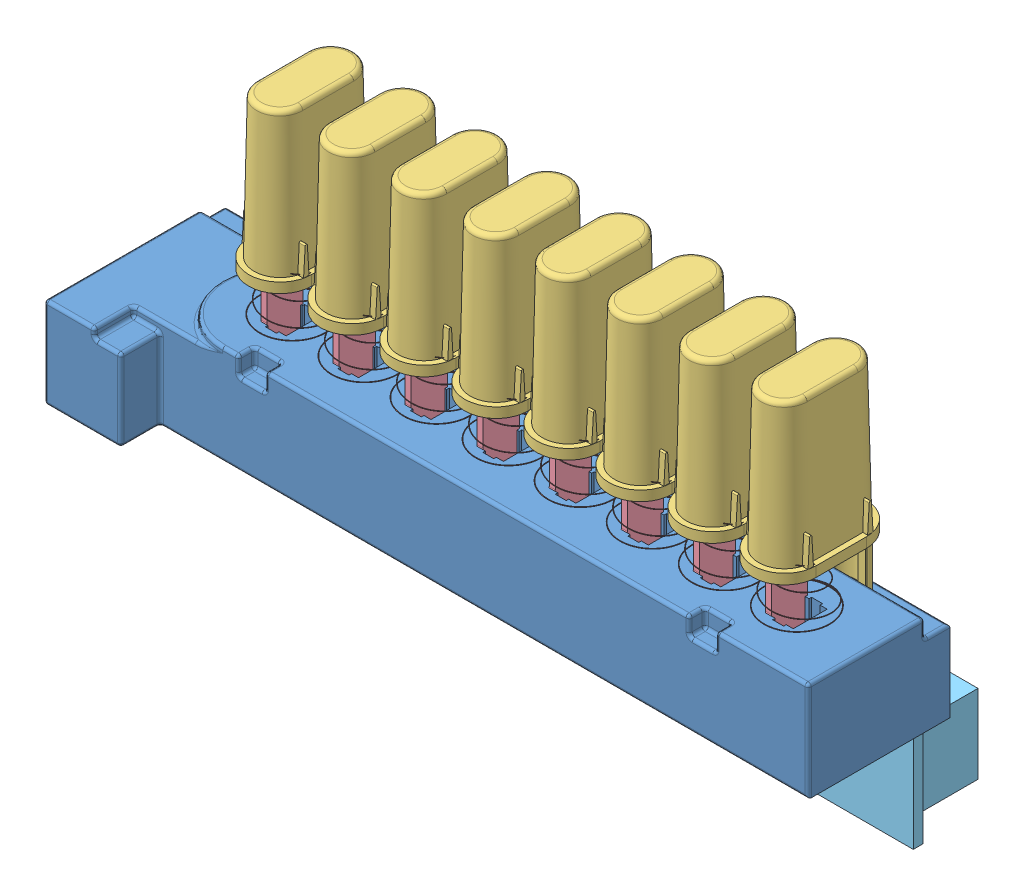
SolidWorks assembly Buttonboxsubassembly, configuration Default. Lengths in mm.
Overall size (116.84 65.25 39.12).
26 component instances, 5 part files, 10 mates.
Components (placement in the parent):
- button box-1: button box [Default] at (46.117 55.4013 86.7134) size (116.84 16 29.21)
- pillaip-spring-1: pillaip-spring [Default] at (11.9321 72.1833 85.5267) size (10.6 9.23 10.6)
- Button-2-1: Button-2 [Default] at (10.105 102.3913 77.544) x (0 0 1) z (1 0 0) size (18.29 33.02 10.16)
- button-key-1: button-key [Default] at (9.6224 72.1653 85.3545) x (0 -1 0) z (0 0 1) size (29.46 0.97 14.24)
- button-key-2: button-key [Default] at (21.2429 72.1653 85.3545) x (0 -1 0) z (0 0 1) size (29.46 0.97 14.24)
- button-key-3: button-key [Default] at (32.8634 72.1653 85.3545) x (0 -1 0) z (0 0 1) size (29.46 0.97 14.24)
- button-key-4: button-key [Default] at (44.4839 72.1653 85.3545) x (0 -1 0) z (0 0 1) size (29.46 0.97 14.24)
- button-key-5: button-key [Default] at (56.1044 72.1653 85.3545) x (0 -1 0) z (0 0 1) size (29.46 0.97 14.24)
- button-key-6: button-key [Default] at (67.7249 72.1653 85.3545) x (0 -1 0) z (0 0 1) size (29.46 0.97 14.24)
- button-key-7: button-key [Default] at (79.3454 72.1653 85.3545) x (0 -1 0) z (0 0 1) size (29.46 0.97 14.24)
- button-key-8: button-key [Default] at (90.9659 72.1653 85.3545) x (0 -1 0) z (0 0 1) size (29.46 0.97 14.24)
- Button-2-2: Button-2 [Default] at (21.7255 102.3913 77.544) x (0 0 1) z (1 0 0) size (18.29 33.02 10.16)
- Button-2-3: Button-2 [Default] at (33.346 102.3913 77.544) x (0 0 1) z (1 0 0) size (18.29 33.02 10.16)
- Button-2-4: Button-2 [Default] at (44.9665 102.3913 77.544) x (0 0 1) z (1 0 0) size (18.29 33.02 10.16)
- Button-2-5: Button-2 [Default] at (56.587 102.3913 77.544) x (0 0 1) z (1 0 0) size (18.29 33.02 10.16)
- Button-2-6: Button-2 [Default] at (68.2075 102.3913 77.544) x (0 0 1) z (1 0 0) size (18.29 33.02 10.16)
- Button-2-7: Button-2 [Default] at (79.828 102.3913 77.544) x (0 0 1) z (1 0 0) size (18.29 33.02 10.16)
- Button-2-8: Button-2 [Default] at (91.4485 102.3913 77.544) x (0 0 1) z (1 0 0) size (18.29 33.02 10.16)
- pillaip-spring-2: pillaip-spring [Default] at (23.5526 72.1833 85.5267) size (10.6 9.23 10.6)
- pillaip-spring-3: pillaip-spring [Default] at (35.1731 72.1833 85.5267) size (10.6 9.23 10.6)
- pillaip-spring-4: pillaip-spring [Default] at (46.7936 72.1833 85.5267) size (10.6 9.23 10.6)
- pillaip-spring-5: pillaip-spring [Default] at (58.4141 72.1833 85.5267) size (10.6 9.23 10.6)
- pillaip-spring-6: pillaip-spring [Default] at (70.0346 72.1833 85.5267) size (10.6 9.23 10.6)
- pillaip-spring-7: pillaip-spring [Default] at (81.6551 72.1833 85.5267) size (10.6 9.23 10.6)
- pillaip-spring-8: pillaip-spring [Default] at (93.2756 72.1833 85.5267) size (10.6 9.23 10.6)
- pillaip-circuitboard-2: pillaip-circuitboard [Default] at (53.1748 50.2958 73.6324) x (-1 0.000001 0) z (0.000001 1 0) size (97.05 12.98 26.31)
Mates (geometry in assembly coordinates):
- Coincident3: coincident anti-aligned: plane of button box-1 through (46.117 57.4333 82.4335) normal (0 0 1); plane of button-key-1 through (140.599 72.1653 82.4335) normal (0 0 -1)
- Coincident4: coincident anti-aligned: plane of button box-1 through (46.117 57.4333 86.7134) normal (0 1 0); plane of button-key-1 through (140.599 57.4333 85.3545) normal (0 -1 0)
- Lock3: lock: unknown of button box-1; unknown of pillaip-spring-1
- Coincident5: coincident anti-aligned: plane of Button-2-1 through (139.6338 100.6133 88.2755) normal (0 0 -1); plane of button-key-1 through (140.599 72.1653 88.2755) normal (0 0 1)
- Coincident6: coincident anti-aligned: plane of Button-2-1 through (140.1164 86.8973 77.544) normal (0 -1 0); plane of button-key-1 through (140.599 86.8973 85.3545) normal (0 1 0)
- Coincident7: coincident anti-aligned: plane of Button-2-1 through (140.599 100.6133 87.6405) normal (-1 0 0); plane of button-key-1 through (140.599 72.1653 85.3545) normal (1 0 0)
- Coincident15: coincident anti-aligned: plane of button box-1 through (46.117 63.4531 86.7134) normal (0 -1 0); plane of pillaip-circuitboard-2 through (53.1748 63.4531 75.1818) normal (0 1 0)
- Coincident17: coincident anti-aligned: plane of button box-1 through (46.117 63.4531 73.6324) normal (0 0 1); plane of pillaip-circuitboard-2 through (53.1748 50.2958 73.6324) normal (0 0 -1)
- Lock5: lock: unknown of button box-1; unknown of pillaip-circuitboard-2
- Coincident26: coincident anti-aligned: plane of button box-1 through (9.6224 57.4333 86.7134) normal (1 0 0); plane of button-key-1 through (9.6224 72.1653 85.3545) normal (-1 0 0)
